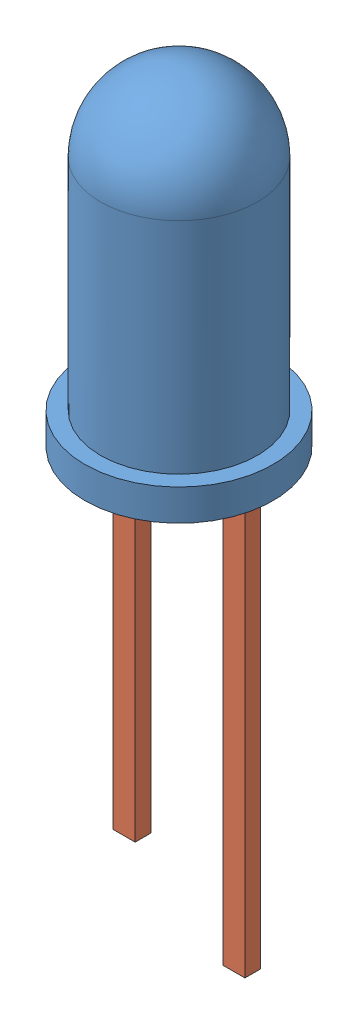
SolidWorks assembly Assem1, configuration Default. Lengths in mm.
Overall size (6 24.14 6).
2 component instances, 2 part files, 1 mates.
Components (placement in the parent):
- Part2-1: Part2 [Default] at (3.3642 2.3943 6.8818) size (6 10.5 6)
- Part1-1: Part1 [Default] at (3.3508 0.4708 6.3663) size (4.2 17 0.5)
Mates (geometry in assembly coordinates):
- Distance1: distance = 0.5 mm anti-aligned: plane of Part1-1 through (4.0508 3.8943 6.8663) normal (0 -1 0); plane of Part2-1 through (3.3642 3.3943 6.8818) normal (0 1 0)
